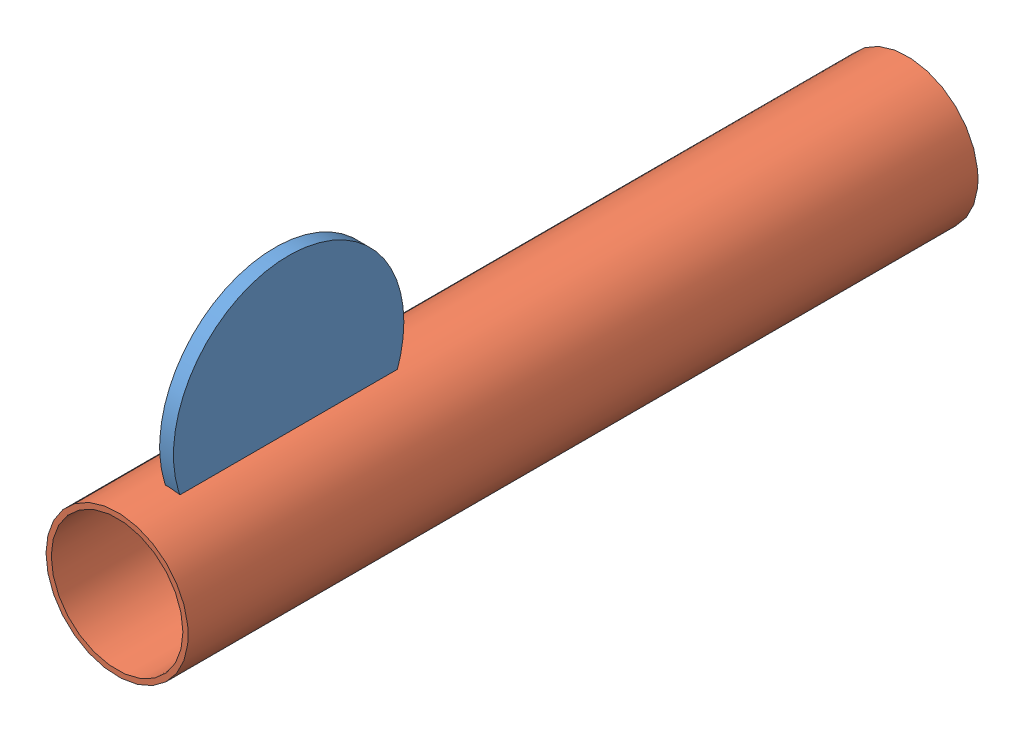
SolidWorks assembly PitcherRelease, configuration Default. Lengths in mm.
Overall size (64.07 118.35 304.8).
3 component instances, 3 part files, 3 mates.
Components (placement in the parent):
- genevaWheel-1: genevaWheel [Default] at (2.9948 41.2379 111.0753) x (0 0 1) z (-1 0 0) size (88.9 88.9 5.33)
- pvc-1: pvc [Default] at (0 0 19.2277) size (54.86 54.86 304.8)
- pingPongBall-1: pingPongBall [Default] at (0 0 92.2827) x (0.56225 -0.47071 0.679932) z (-0.390358 0.573768 0.720008) size (38.1 38.1 38.1)
Mates (geometry in assembly coordinates):
- Parallel3: parallel anti-aligned: plane of genevaWheel-1 through (0.3278 41.2379 111.0753) normal (-1 0 0); plane of assembly through (0 0 0) normal (1 0 0)
- Concentric1: concentric: cylinder of pvc-1 through (0 0 -133.1723) axis (0 0 1) radius 25.4; sphere of pingPongBall-1
- Concentric2: concentric aligned: cylinder of pvc-1 through (0 0 171.6277) axis (0 0 -1) radius 27.432
